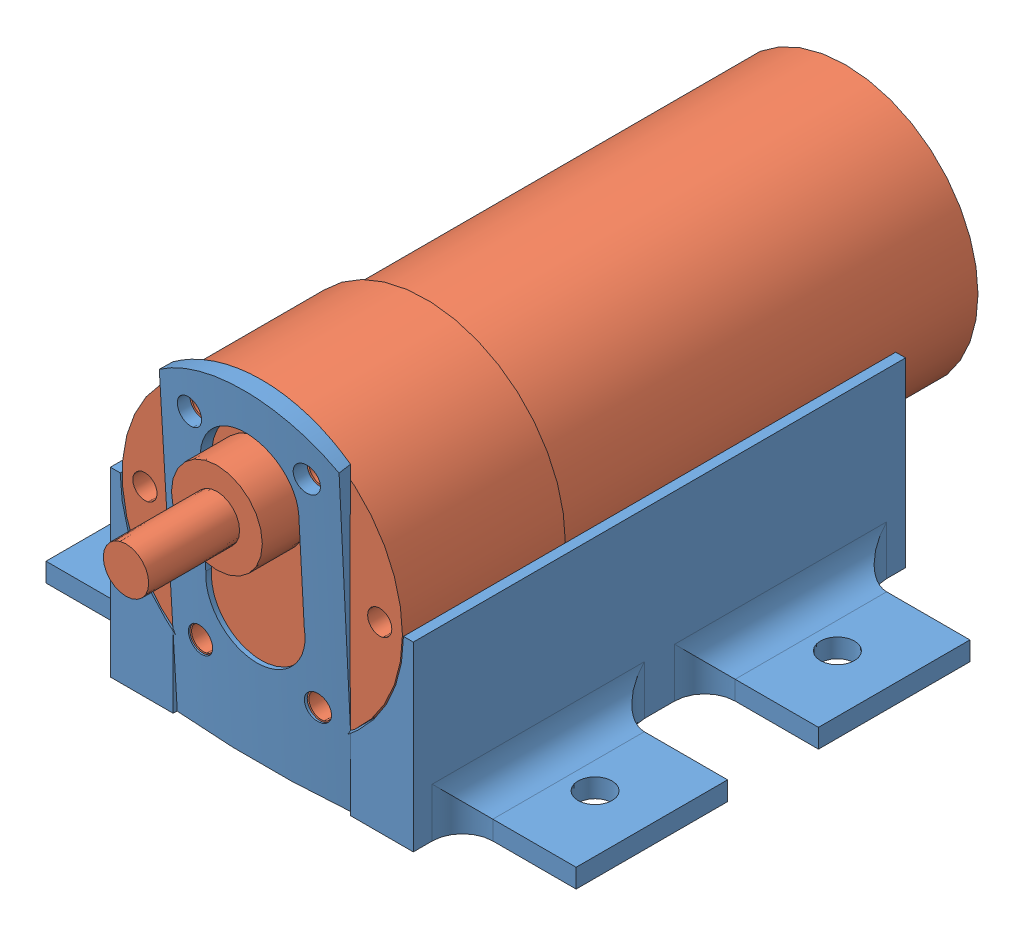
SolidWorks assembly Montagem_motor, configuration Valor predeterminado. Lengths in mm.
Overall size (70 44 95).
2 component instances, 2 part files, 0 mates.
Components (placement in the parent):
- Capa para o motor-1: Capa para o motor [Valor predeterminado] at (-31.8318 -13.461 70.9319) size (70 44 68.53)
- motor-1: motor [Valor predeterminado] at (-11.8318 10.539 135.8679) size (37 37 95)
